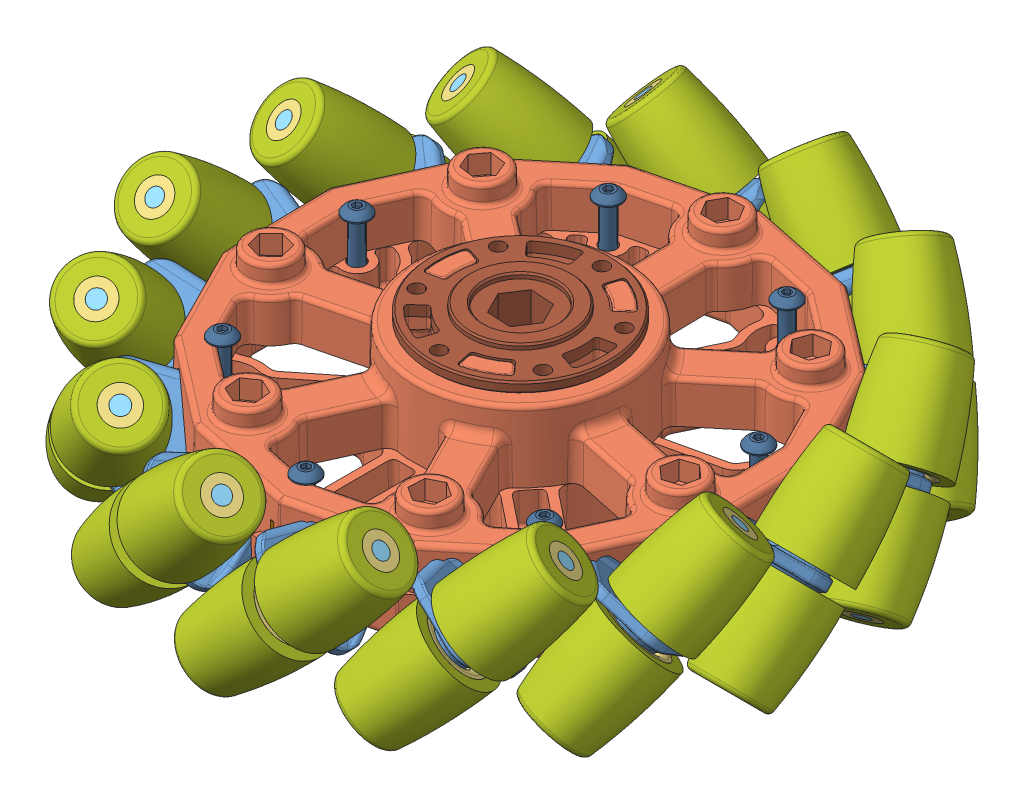
SolidWorks assembly 8in mecanum left vex 217-2801, configuration Default. Lengths in mm.
Overall size (213.38 67.99 218.38).
149 component instances, 11 part files, 3 mates.
Components (placement in the parent):
- 217-2799-002 Rev1-1: 217-2799-002 Rev1 [Default] at (67.5204 0 0) x (0 0 -1) z (1 0 0) size (26.84 25.28 30.09)
- 217-2801-001 Rev1-1: 217-2801-001 Rev1 [Default] at (-0.0396 6.3542 -0.0405) x (1 0 0) z (0 -1 0) size (148.4 151.99 28.55)
- 217-2801-001 Rev1-2: 217-2801-001 Rev1 [Default] at (0.6081 -6.3458 -2.0155) x (-0.892252 0 0.451538) z (0 1 0) size (148.4 151.99 28.55)
- 217-2586-003 Rev2-1: 217-2586-003 Rev2 [Default] at (88.2976 -4.0062 4.0062) x (-0.854327 -0.367509 -0.367509) z (-0.519737 0.6041 0.6041) size (19.46 28.57 19.46)
- 217-2586-003 Rev2-2: 217-2586-003 Rev2 [Default] at (88.2976 4.0062 -4.0062) x (0.717269 -0.492709 -0.492709) z (0.696796 0.507186 0.507186) size (19.46 28.57 19.46)
- 217-2586-005 Rev2-1: 217-2586-005 Rev2 [Default] at (88.2976 -6.3286 6.3286) x (0 0.707107 -0.707107) z (0.473193 -0.622932 -0.622932) size (8.5 8 8)
- 217-2586-005 Rev2-2: 217-2586-005 Rev2 [Default] at (88.2976 6.3286 -6.3286) x (0 0.707107 -0.707107) z (0.707107 -0.5 -0.5) size (8.5 8 8)
- 217-2586-007 Rev1-1: 217-2586-007 Rev1 [Default] at (88.2976 0 0) x (0 0.707107 -0.707107) z (0.543569 -0.59352 -0.59352) size (61.72 5 5)
- 217-2586-008 Rev1-1: 217-2586-008 Rev1 [Default] at (-11.9459 2.5442 -20.6627) x (0.866025 0 -0.5) z (0 -1 0) size (7.33 6.35 31.75)
- 217-2587-002 Rev2-1: 217-2587-002 Rev2 [Default] at (88.2976 -0.3986 0.3986) x (-0.963241 0.189956 0.189956) z (-0.268638 -0.681114 -0.681114) size (26.1 28.57 26.1)
- 217-2587-002 Rev2-2: 217-2587-002 Rev2 [Default] at (88.2976 0.3986 -0.3986) x (0.779223 -0.443177 -0.443177) z (-0.626747 -0.550994 -0.550994) size (26.1 28.57 26.1)
- NUT-832-NYLOCK-1: NUT-832-NYLOCK [Default] at (-49.6859 -13.6521 39.5511) x (-0.365341 0 0.930874) z (0.930874 0 0.365341) size (10.2 5.86 8.12)
- PINL-M050-0012-S-1: PINL-M050-0012-S [Default] at (-69.318 -0.0958 -15.8528) x (0 -1 0) z (-0.272222 0 0.962235) size (12 5 5)
- SCREW-832-1250-1: SCREW-832-1250 [Default] at (-49.6859 14.914 39.5511) x (0 -1 0) z (-0.321403 0 -0.946943) size (33.96 7.92 7.92)
- 217-2586-008 Rev1-2: 217-2586-008 Rev1 [Default] at (-23.8521 2.5442 -0.0405) x (0 0 -1) z (0 -1 0) size (7.33 6.35 31.75)
- 217-2586-008 Rev1-3: 217-2586-008 Rev1 [Default] at (-15.8036 2.5442 6.5601) x (-0.667084 0 -0.744983) z (0 -1 0) size (7.33 6.35 31.75)
- 217-2586-008 Rev1-4: 217-2586-008 Rev1 [Default] at (11.8666 2.5442 20.5817) x (-0.866025 0 0.5) z (0 -1 0) size (7.33 6.35 31.75)
- 217-2586-008 Rev1-5: 217-2586-008 Rev1 [Default] at (23.7729 2.5442 -0.0405) x (0 0 1) z (0 -1 0) size (7.33 6.35 31.75)
- 217-2586-008 Rev1-6: 217-2586-008 Rev1 [Default] at (11.8666 2.5442 -20.6627) x (0.866025 0 0.5) z (0 -1 0) size (7.33 6.35 31.75)
- NUT-832-NYLOCK-2: NUT-832-NYLOCK [Default] at (-0.0396 -13.6521 63.4595) x (0.5 0 0.866025) z (0.866025 0 -0.5) size (10.2 5.86 8.12)
- NUT-832-NYLOCK-3: NUT-832-NYLOCK [Default] at (49.6067 -13.6521 39.5511) x (0.988831 0 0.149042) z (0.149042 0 -0.988831) size (10.2 5.86 8.12)
- NUT-832-NYLOCK-4: NUT-832-NYLOCK [Default] at (61.8683 -13.6521 -14.1706) x (0.733052 0 -0.680173) z (-0.680173 0 -0.733052) size (10.2 5.86 8.12)
- NUT-832-NYLOCK-5: NUT-832-NYLOCK [Default] at (27.512 -13.6521 -57.252) x (-0.07473 0 -0.997204) z (-0.997204 0 0.07473) size (10.2 5.86 8.12)
- NUT-832-NYLOCK-6: NUT-832-NYLOCK [Default] at (-27.5912 -13.6521 -57.252) x (-0.826239 0 -0.56332) z (-0.56332 0 0.826239) size (10.2 5.86 8.12)
- NUT-832-NYLOCK-7: NUT-832-NYLOCK [Default] at (-61.9475 -13.6521 -14.1706) x (-0.955573 0 0.294755) z (0.294755 0 0.955573) size (10.2 5.86 8.12)
- SCREW-832-1250-2: SCREW-832-1250 [Default] at (-0.0396 14.914 63.4595) x (0 -1 0) z (-0.940741 0 -0.339126) size (33.96 7.92 7.92)
- SCREW-832-1250-3: SCREW-832-1250 [Default] at (49.6067 14.914 39.5511) x (0 -1 0) z (-0.851682 0 0.524059) size (33.96 7.92 7.92)
- SCREW-832-1250-4: SCREW-832-1250 [Default] at (61.8683 14.914 -14.1706) x (0 -1 0) z (-0.121289 0 0.992617) size (33.96 7.92 7.92)
- SCREW-832-1250-5: SCREW-832-1250 [Default] at (27.512 14.914 -57.252) x (0 -1 0) z (0.700437 0 0.713714) size (33.96 7.92 7.92)
- SCREW-832-1250-6: SCREW-832-1250 [Default] at (-27.5912 14.914 -57.252) x (0 -1 0) z (0.99472 0 -0.10263) size (33.96 7.92 7.92)
- SCREW-832-1250-7: SCREW-832-1250 [Default] at (-61.9475 14.914 -14.1706) x (0 -1 0) z (0.539958 0 -0.841692) size (33.96 7.92 7.92)
- PINL-M050-0012-S-2: PINL-M050-0012-S [Default] at (-69.318 -0.0958 15.7719) x (0 -1 0) z (0.172235 0 0.985056) size (12 5 5)
- PINL-M050-0012-S-3: PINL-M050-0012-S [Default] at (-55.5966 -0.0958 44.2647) x (0 -1 0) z (0.582578 0 0.812775) size (12 5 5)
- PINL-M050-0012-S-4: PINL-M050-0012-S [Default] at (-30.8714 -0.0958 63.9824) x (0 -1 0) z (0.877534 0 0.479514) size (12 5 5)
- PINL-M050-0012-S-5: PINL-M050-0012-S [Default] at (-0.0396 -0.0958 71.0195) x (0 -1 0) z (0.998684 0 0.051279) size (12 5 5)
- PINL-M050-0012-S-6: PINL-M050-0012-S [Default] at (30.7922 -0.0958 63.9824) x (0 -1 0) z (0.922033 0 -0.387112) size (12 5 5)
- PINL-M050-0012-S-7: PINL-M050-0012-S [Default] at (55.5173 -0.0958 44.2647) x (0 -1 0) z (0.662761 0 -0.748831) size (12 5 5)
- PINL-M050-0012-S-8: PINL-M050-0012-S [Default] at (69.2388 -0.0958 15.7719) x (0 -1 0) z (0.272222 0 -0.962235) size (12 5 5)
- PINL-M050-0012-S-9: PINL-M050-0012-S [Default] at (69.2388 -0.0958 -15.8528) x (0 -1 0) z (-0.172235 0 -0.985056) size (12 5 5)
- PINL-M050-0012-S-10: PINL-M050-0012-S [Default] at (55.5173 -0.0958 -44.3457) x (0 -1 0) z (-0.582578 0 -0.812775) size (12 5 5)
- PINL-M050-0012-S-11: PINL-M050-0012-S [Default] at (30.7922 -0.0958 -64.0633) x (0 -1 0) z (-0.877534 0 -0.479514) size (12 5 5)
- PINL-M050-0012-S-12: PINL-M050-0012-S [Default] at (-0.0396 -0.0958 -71.1005) x (0 -1 0) z (-0.998684 0 -0.051279) size (12 5 5)
- PINL-M050-0012-S-13: PINL-M050-0012-S [Default] at (-30.8714 -0.0958 -64.0633) x (0 -1 0) z (-0.922033 0 0.387112) size (12 5 5)
- PINL-M050-0012-S-14: PINL-M050-0012-S [Default] at (-55.5966 -0.0958 -44.3457) x (0 -1 0) z (-0.662761 0 0.748831) size (12 5 5)
- 217-2587-002 Rev2-3: 217-2587-002 Rev2 [Default] at (79.3941 0.3986 -38.6912) x (0.509769 -0.443177 -0.737381) z (-0.803746 -0.550994 -0.224493) size (26.1 28.57 26.1)
- 217-2587-002 Rev2-4: 217-2587-002 Rev2 [Default] at (54.7578 0.3986 -69.3286) x (0.139348 -0.443177 -0.885537) z (-0.821555 -0.550994 0.146471) size (26.1 28.57 26.1)
- 217-2587-002 Rev2-5: 217-2587-002 Rev2 [Default] at (19.2682 0.3986 -86.2426) x (-0.258672 -0.443177 -0.858303) z (-0.676644 -0.550994 0.488425) size (26.1 28.57 26.1)
- 217-2587-002 Rev2-6: 217-2587-002 Rev2 [Default] at (-20.0456 0.3986 -86.0832) x (-0.605459 -0.443177 -0.66107) z (-0.397715 -0.550994 0.73364) size (26.1 28.57 26.1)
- 217-2587-002 Rev2-7: 217-2587-002 Rev2 [Default] at (-55.3969 0.3986 -68.882) x (-0.832327 -0.443177 -0.332905) z (-0.040014 -0.550994 0.833549) size (26.1 28.57 26.1)
- 217-2587-002 Rev2-8: 217-2587-002 Rev2 [Default] at (-79.784 0.3986 -38.0459) x (-0.894343 -0.443177 0.061196) z (0.325612 -0.550994 0.768364) size (26.1 28.57 26.1)
- 217-2587-002 Rev2-9: 217-2587-002 Rev2 [Default] at (-88.3768 0.3986 0.3176) x (-0.779223 -0.443177 0.443177) z (0.626747 -0.550994 0.550994) size (26.1 28.57 26.1)
- 217-2587-002 Rev2-10: 217-2587-002 Rev2 [Default] at (-79.4733 0.3986 38.6102) x (-0.509769 -0.443177 0.737381) z (0.803746 -0.550994 0.224493) size (26.1 28.57 26.1)
- 217-2587-002 Rev2-11: 217-2587-002 Rev2 [Default] at (-54.837 0.3986 69.2476) x (-0.139348 -0.443177 0.885537) z (0.821555 -0.550994 -0.146471) size (26.1 28.57 26.1)
- 217-2587-002 Rev2-12: 217-2587-002 Rev2 [Default] at (-19.3474 0.3986 86.1616) x (0.258672 -0.443177 0.858303) z (0.676644 -0.550994 -0.488425) size (26.1 28.57 26.1)
- 217-2587-002 Rev2-13: 217-2587-002 Rev2 [Default] at (19.9664 0.3986 86.0022) x (0.605459 -0.443177 0.66107) z (0.397715 -0.550994 -0.73364) size (26.1 28.57 26.1)
- 217-2587-002 Rev2-14: 217-2587-002 Rev2 [Default] at (55.3177 0.3986 68.8011) x (0.832327 -0.443177 0.332905) z (0.040014 -0.550994 -0.833549) size (26.1 28.57 26.1)
- 217-2587-002 Rev2-15: 217-2587-002 Rev2 [Default] at (79.7048 0.3986 37.965) x (0.894343 -0.443177 -0.061196) z (-0.325612 -0.550994 -0.768364) size (26.1 28.57 26.1)
- 217-2587-002 Rev2-16: 217-2587-002 Rev2 [Default] at (79.74 -0.3986 -37.973) x (-0.785432 0.189956 0.589079) z (-0.537559 -0.681114 -0.497105) size (26.1 28.57 26.1)
- 217-2587-002 Rev2-17: 217-2587-002 Rev2 [Default] at (55.381 -0.3986 -68.8315) x (-0.452058 0.189956 0.871528) z (-0.70001 -0.681114 -0.214638) size (26.1 28.57 26.1)
- 217-2587-002 Rev2-18: 217-2587-002 Rev2 [Default] at (20.0453 -0.3986 -86.0652) x (-0.029148 0.189956 0.98136) z (-0.723815 -0.681114 0.110341) size (26.1 28.57 26.1)
- 217-2587-002 Rev2-19: 217-2587-002 Rev2 [Default] at (-19.2684 -0.3986 -86.2606) x (0.399535 0.189956 0.896822) z (-0.60426 -0.681114 0.413465) size (26.1 28.57 26.1)
- 217-2587-002 Rev2-20: 217-2587-002 Rev2 [Default] at (-54.7737 -0.3986 -69.379) x (0.749084 0.189956 0.634657) z (-0.365024 -0.681114 0.634698) size (26.1 28.57 26.1)
- 217-2587-002 Rev2-21: 217-2587-002 Rev2 [Default] at (-79.4382 -0.3986 -38.7641) x (0.950269 0.189956 0.24679) z (-0.05349 -0.681114 0.730221) size (26.1 28.57 26.1)
- 217-2587-002 Rev2-22: 217-2587-002 Rev2 [Default] at (-88.3768 -0.3986 -0.4795) x (0.963241 0.189956 -0.189956) z (0.268638 -0.681114 0.681114) size (26.1 28.57 26.1)
- 217-2587-002 Rev2-23: 217-2587-002 Rev2 [Default] at (-79.8192 -0.3986 37.892) x (0.785432 0.189956 -0.589079) z (0.537559 -0.681114 0.497105) size (26.1 28.57 26.1)
- 217-2587-002 Rev2-24: 217-2587-002 Rev2 [Default] at (-55.4602 -0.3986 68.7506) x (0.452058 0.189956 -0.871528) z (0.70001 -0.681114 0.214638) size (26.1 28.57 26.1)
- 217-2587-002 Rev2-25: 217-2587-002 Rev2 [Default] at (-20.1245 -0.3986 85.9842) x (0.029148 0.189956 -0.98136) z (0.723815 -0.681114 -0.110341) size (26.1 28.57 26.1)
- 217-2587-002 Rev2-26: 217-2587-002 Rev2 [Default] at (19.1892 -0.3986 86.1796) x (-0.399535 0.189956 -0.896822) z (0.60426 -0.681114 -0.413465) size (26.1 28.57 26.1)
- 217-2587-002 Rev2-27: 217-2587-002 Rev2 [Default] at (54.6945 -0.3986 69.2981) x (-0.749084 0.189956 -0.634657) z (0.365024 -0.681114 -0.634698) size (26.1 28.57 26.1)
- 217-2587-002 Rev2-28: 217-2587-002 Rev2 [Default] at (79.359 -0.3986 38.6832) x (-0.950269 0.189956 -0.24679) z (0.05349 -0.681114 -0.730221) size (26.1 28.57 26.1)
- 217-2586-007 Rev1-2: 217-2586-007 Rev1 [Default] at (79.567 0 -38.3321) x (-0.306802 0.707107 -0.637081) z (0.23222 -0.59352 -0.770589) size (61.72 5 5)
- 217-2586-007 Rev1-3: 217-2586-007 Rev1 [Default] at (55.0694 0 -69.08) x (-0.552838 0.707107 -0.440874) z (-0.125123 -0.59352 -0.795033) size (61.72 5 5)
- 217-2586-007 Rev1-4: 217-2586-007 Rev1 [Default] at (19.6567 0 -86.1539) x (-0.689378 0.707107 -0.157346) z (-0.457684 -0.59352 -0.662011) size (61.72 5 5)
- 217-2586-007 Rev1-5: 217-2586-007 Rev1 [Default] at (-19.657 0 -86.1719) x (-0.689378 0.707107 0.157346) z (-0.699595 -0.59352 -0.39787) size (61.72 5 5)
- 217-2586-007 Rev1-6: 217-2586-007 Rev1 [Default] at (-55.0853 0 -69.1305) x (-0.552838 0.707107 0.440874) z (-0.802943 -0.59352 -0.054926) size (61.72 5 5)
- 217-2586-007 Rev1-7: 217-2586-007 Rev1 [Default] at (-79.6111 0 -38.405) x (-0.306802 0.707107 0.637081) z (-0.747258 -0.59352 0.298897) size (61.72 5 5)
- 217-2586-007 Rev1-8: 217-2586-007 Rev1 [Default] at (-88.3768 0 -0.081) x (0 0.707107 0.707107) z (-0.543569 -0.59352 0.59352) size (61.72 5 5)
- 217-2586-007 Rev1-9: 217-2586-007 Rev1 [Default] at (-79.6462 0 38.2511) x (0.306802 0.707107 0.637081) z (-0.23222 -0.59352 0.770589) size (61.72 5 5)
- 217-2586-007 Rev1-10: 217-2586-007 Rev1 [Default] at (-55.1486 0 68.9991) x (0.552838 0.707107 0.440874) z (0.125123 -0.59352 0.795033) size (61.72 5 5)
- 217-2586-007 Rev1-11: 217-2586-007 Rev1 [Default] at (-19.736 0 86.0729) x (0.689378 0.707107 0.157346) z (0.457684 -0.59352 0.662011) size (61.72 5 5)
- 217-2586-007 Rev1-12: 217-2586-007 Rev1 [Default] at (19.5778 0 86.0909) x (0.689378 0.707107 -0.157346) z (0.699595 -0.59352 0.39787) size (61.72 5 5)
- 217-2586-007 Rev1-13: 217-2586-007 Rev1 [Default] at (55.0061 0 69.0496) x (0.552838 0.707107 -0.440874) z (0.802943 -0.59352 0.054926) size (61.72 5 5)
- 217-2586-007 Rev1-14: 217-2586-007 Rev1 [Default] at (79.5319 0 38.3241) x (0.306802 0.707107 -0.637081) z (0.747258 -0.59352 -0.298897) size (61.72 5 5)
- 217-2586-005 Rev2-3: 217-2586-005 Rev2 [Default] at (76.8211 6.3286 -44.034) x (-0.306802 0.707107 -0.637081) z (0.420139 -0.5 -0.757287) size (8.5 8 8)
- 217-2586-005 Rev2-4: 217-2586-005 Rev2 [Default] at (50.1215 6.3286 -73.0259) x (-0.552838 0.707107 -0.440874) z (0.049958 -0.5 -0.864583) size (8.5 8 8)
- 217-2586-005 Rev2-5: 217-2586-005 Rev2 [Default] at (13.4868 6.3286 -87.5621) x (-0.689378 0.707107 -0.157346) z (-0.330118 -0.5 -0.800639) size (8.5 8 8)
- 217-2586-005 Rev2-6: 217-2586-005 Rev2 [Default] at (-25.827 6.3286 -84.7636) x (-0.689378 0.707107 0.157346) z (-0.64481 -0.5 -0.578118) size (8.5 8 8)
- 217-2586-005 Rev2-7: 217-2586-005 Rev2 [Default] at (-60.0332 6.3286 -65.1847) x (-0.552838 0.707107 0.440874) z (-0.83179 -0.5 -0.241093) size (8.5 8 8)
- 217-2586-005 Rev2-8: 217-2586-005 Rev2 [Default] at (-82.357 6.3286 -32.7032) x (-0.306802 0.707107 0.637081) z (-0.854023 -0.5 0.143682) size (8.5 8 8)
- 217-2586-005 Rev2-9: 217-2586-005 Rev2 [Default] at (-88.3768 6.3286 6.2476) x (0 0.707107 0.707107) z (-0.707107 -0.5 0.5) size (8.5 8 8)
- 217-2586-005 Rev2-10: 217-2586-005 Rev2 [Default] at (-76.9004 6.3286 43.953) x (0.306802 0.707107 0.637081) z (-0.420139 -0.5 0.757287) size (8.5 8 8)
- 217-2586-005 Rev2-11: 217-2586-005 Rev2 [Default] at (-50.2007 6.3286 72.9449) x (0.552838 0.707107 0.440874) z (-0.049958 -0.5 0.864583) size (8.5 8 8)
- 217-2586-005 Rev2-12: 217-2586-005 Rev2 [Default] at (-13.566 6.3286 87.4812) x (0.689378 0.707107 0.157346) z (0.330118 -0.5 0.800639) size (8.5 8 8)
- 217-2586-005 Rev2-13: 217-2586-005 Rev2 [Default] at (25.7477 6.3286 84.6827) x (0.689378 0.707107 -0.157346) z (0.64481 -0.5 0.578118) size (8.5 8 8)
- 217-2586-005 Rev2-14: 217-2586-005 Rev2 [Default] at (59.954 6.3286 65.1037) x (0.552838 0.707107 -0.440874) z (0.83179 -0.5 0.241093) size (8.5 8 8)
- 217-2586-005 Rev2-15: 217-2586-005 Rev2 [Default] at (82.2778 6.3286 32.6222) x (0.306802 0.707107 -0.637081) z (0.854023 -0.5 -0.143682) size (8.5 8 8)
- 217-2586-005 Rev2-16: 217-2586-005 Rev2 [Default] at (82.3129 -6.3286 -32.6302) x (-0.306802 0.707107 -0.637081) z (0.156052 -0.622932 -0.766553) size (8.5 8 8)
- 217-2586-005 Rev2-17: 217-2586-005 Rev2 [Default] at (60.0173 -6.3286 -65.1342) x (-0.552838 0.707107 -0.440874) z (-0.191997 -0.622932 -0.758349) size (8.5 8 8)
- 217-2586-005 Rev2-18: 217-2586-005 Rev2 [Default] at (25.8267 -6.3286 -84.7456) x (-0.689378 0.707107 -0.157346) z (-0.502019 -0.622932 -0.599944) size (8.5 8 8)
- 217-2586-005 Rev2-19: 217-2586-005 Rev2 [Default] at (-13.4871 -6.3286 -87.5801) x (-0.689378 0.707107 0.157346) z (-0.712609 -0.622932 -0.322713) size (8.5 8 8)
- 217-2586-005 Rev2-20: 217-2586-005 Rev2 [Default] at (-50.1374 -6.3286 -73.0764) x (-0.552838 0.707107 0.440874) z (-0.782059 -0.622932 0.018435) size (8.5 8 8)
- 217-2586-005 Rev2-21: 217-2586-005 Rev2 [Default] at (-76.8652 -6.3286 -44.1069) x (-0.306802 0.707107 0.637081) z (-0.696612 -0.622932 0.355932) size (8.5 8 8)
- 217-2586-005 Rev2-22: 217-2586-005 Rev2 [Default] at (-88.3768 -6.3286 -6.4096) x (0 0.707107 0.707107) z (-0.473193 -0.622932 0.622932) size (8.5 8 8)
- 217-2586-005 Rev2-23: 217-2586-005 Rev2 [Default] at (-82.3921 -6.3286 32.5492) x (0.306802 0.707107 0.637081) z (-0.156052 -0.622932 0.766553) size (8.5 8 8)
- 217-2586-005 Rev2-24: 217-2586-005 Rev2 [Default] at (-60.0965 -6.3286 65.0533) x (0.552838 0.707107 0.440874) z (0.191997 -0.622932 0.758349) size (8.5 8 8)
- 217-2586-005 Rev2-25: 217-2586-005 Rev2 [Default] at (-25.9059 -6.3286 84.6647) x (0.689378 0.707107 0.157346) z (0.502019 -0.622932 0.599944) size (8.5 8 8)
- 217-2586-005 Rev2-26: 217-2586-005 Rev2 [Default] at (13.4079 -6.3286 87.4992) x (0.689378 0.707107 -0.157346) z (0.712609 -0.622932 0.322713) size (8.5 8 8)
- 217-2586-005 Rev2-27: 217-2586-005 Rev2 [Default] at (50.0582 -6.3286 72.9954) x (0.552838 0.707107 -0.440874) z (0.782059 -0.622932 -0.018435) size (8.5 8 8)
- 217-2586-005 Rev2-28: 217-2586-005 Rev2 [Default] at (76.786 -6.3286 44.0259) x (0.306802 0.707107 -0.637081) z (0.696612 -0.622932 -0.355932) size (8.5 8 8)
- 217-2586-003 Rev2-3: 217-2586-003 Rev2 [Default] at (77.8288 4.0062 -41.9416) x (0.432459 -0.492709 -0.755127) z (0.847851 0.507186 0.15463) size (19.46 28.57 19.46)
- 217-2586-003 Rev2-4: 217-2586-003 Rev2 [Default] at (51.9372 4.0062 -71.5779) x (0.061995 -0.492709 -0.867983) z (0.830979 0.507186 -0.228552) size (19.46 28.57 19.46)
- 217-2586-003 Rev2-5: 217-2586-003 Rev2 [Default] at (15.7509 4.0062 -87.0453) x (-0.320749 -0.492709 -0.808924) z (0.649521 0.507186 -0.566466) size (19.46 28.57 19.46)
- 217-2586-003 Rev2-6: 217-2586-003 Rev2 [Default] at (-23.5628 4.0062 -85.2804) x (-0.639963 -0.492709 -0.589648) z (0.339418 0.507186 -0.792185) size (19.46 28.57 19.46)
- 217-2586-003 Rev2-7: 217-2586-003 Rev2 [Default] at (-58.2175 4.0062 -66.6327) x (-0.832426 -0.492709 -0.253585) z (-0.037911 0.507186 -0.861002) size (19.46 28.57 19.46)
- 217-2586-003 Rev2-8: 217-2586-003 Rev2 [Default] at (-81.3494 4.0062 -34.7955) x (-0.860016 -0.492709 0.132704) z (-0.407732 0.507186 -0.759287) size (19.46 28.57 19.46)
- 217-2586-003 Rev2-9: 217-2586-003 Rev2 [Default] at (-88.3768 4.0062 3.9253) x (-0.717269 -0.492709 0.492709) z (-0.696796 0.507186 -0.507186) size (19.46 28.57 19.46)
- 217-2586-003 Rev2-10: 217-2586-003 Rev2 [Default] at (-77.908 4.0062 41.8606) x (-0.432459 -0.492709 0.755127) z (-0.847851 0.507186 -0.15463) size (19.46 28.57 19.46)
- 217-2586-003 Rev2-11: 217-2586-003 Rev2 [Default] at (-52.0164 4.0062 71.4969) x (-0.061995 -0.492709 0.867983) z (-0.830979 0.507186 0.228552) size (19.46 28.57 19.46)
- 217-2586-003 Rev2-12: 217-2586-003 Rev2 [Default] at (-15.8302 4.0062 86.9644) x (0.320749 -0.492709 0.808924) z (-0.649521 0.507186 0.566466) size (19.46 28.57 19.46)
- 217-2586-003 Rev2-13: 217-2586-003 Rev2 [Default] at (23.4836 4.0062 85.1995) x (0.639963 -0.492709 0.589648) z (-0.339418 0.507186 0.792185) size (19.46 28.57 19.46)
- 217-2586-003 Rev2-14: 217-2586-003 Rev2 [Default] at (58.1383 4.0062 66.5517) x (0.832426 -0.492709 0.253585) z (0.037911 0.507186 0.861002) size (19.46 28.57 19.46)
- 217-2586-003 Rev2-15: 217-2586-003 Rev2 [Default] at (81.2701 4.0062 34.7146) x (0.860016 -0.492709 -0.132704) z (0.407732 0.507186 0.759287) size (19.46 28.57 19.46)
- 217-2586-003 Rev2-16: 217-2586-003 Rev2 [Default] at (81.3053 -4.0062 -34.7226) x (-0.929178 -0.367509 0.039564) z (-0.206157 0.6041 0.769781) size (19.46 28.57 19.46)
- 217-2586-003 Rev2-17: 217-2586-003 Rev2 [Default] at (58.2016 -4.0062 -66.5822) x (-0.819994 -0.367509 0.438801) z (0.148254 0.6041 0.782997) size (19.46 28.57 19.46)
- 217-2586-003 Rev2-18: 217-2586-003 Rev2 [Default] at (23.5625 -4.0062 -85.2624) x (-0.548401 -0.367509 0.751128) z (0.473302 0.6041 0.641131) size (19.46 28.57 19.46)
- 217-2586-003 Rev2-19: 217-2586-003 Rev2 [Default] at (-15.7512 -4.0062 -87.0634) x (-0.16819 -0.367509 0.914685) z (0.704606 0.6041 0.372281) size (19.46 28.57 19.46)
- 217-2586-003 Rev2-20: 217-2586-003 Rev2 [Default] at (-51.9531 -4.0062 -71.6284) x (0.245334 -0.367509 0.897078) z (0.796355 0.6041 0.029696) size (19.46 28.57 19.46)
- 217-2586-003 Rev2-21: 217-2586-003 Rev2 [Default] at (-77.8729 -4.0062 -42.0145) x (0.610265 -0.367509 0.701793) z (0.730376 0.6041 -0.31877) size (19.46 28.57 19.46)
- 217-2586-003 Rev2-22: 217-2586-003 Rev2 [Default] at (-88.3768 -4.0062 -4.0872) x (0.854327 -0.367509 0.367509) z (0.519737 0.6041 -0.6041) size (19.46 28.57 19.46)
- 217-2586-003 Rev2-23: 217-2586-003 Rev2 [Default] at (-81.3845 -4.0062 34.6416) x (0.929178 -0.367509 -0.039564) z (0.206157 0.6041 -0.769781) size (19.46 28.57 19.46)
- 217-2586-003 Rev2-24: 217-2586-003 Rev2 [Default] at (-58.2808 -4.0062 66.5012) x (0.819994 -0.367509 -0.438801) z (-0.148254 0.6041 -0.782997) size (19.46 28.57 19.46)
- 217-2586-003 Rev2-25: 217-2586-003 Rev2 [Default] at (-23.6417 -4.0062 85.1814) x (0.548401 -0.367509 -0.751128) z (-0.473302 0.6041 -0.641131) size (19.46 28.57 19.46)
- 217-2586-003 Rev2-26: 217-2586-003 Rev2 [Default] at (15.672 -4.0062 86.9824) x (0.16819 -0.367509 -0.914685) z (-0.704606 0.6041 -0.372281) size (19.46 28.57 19.46)
- 217-2586-003 Rev2-27: 217-2586-003 Rev2 [Default] at (51.8739 -4.0062 71.5474) x (-0.245334 -0.367509 -0.897078) z (-0.796355 0.6041 -0.029696) size (19.46 28.57 19.46)
- 217-2586-003 Rev2-28: 217-2586-003 Rev2 [Default] at (77.7937 -4.0062 41.9336) x (-0.610265 -0.367509 -0.701793) z (-0.730376 0.6041 0.31877) size (19.46 28.57 19.46)
- 217-2799-002 Rev1-2: 217-2799-002 Rev1 [Default] at (60.8474 0 -29.3172) x (-0.433884 0 -0.900969) z (0.900969 0 -0.433884) size (26.84 25.28 30.09)
- 217-2799-002 Rev1-3: 217-2799-002 Rev1 [Default] at (42.115 0 -52.8358) x (-0.781831 0 -0.62349) z (0.62349 0 -0.781831) size (26.84 25.28 30.09)
- 217-2799-002 Rev1-4: 217-2799-002 Rev1 [Default] at (15.0334 0 -65.8976) x (-0.974928 0 -0.222521) z (0.222521 0 -0.974928) size (26.84 25.28 30.09)
- 217-2799-002 Rev1-5: 217-2799-002 Rev1 [Default] at (-15.0337 0 -65.9156) x (-0.974928 0 0.222521) z (-0.222521 0 -0.974928) size (26.84 25.28 30.09)
- 217-2799-002 Rev1-6: 217-2799-002 Rev1 [Default] at (-42.1309 0 -52.8863) x (-0.781831 0 0.62349) z (-0.62349 0 -0.781831) size (26.84 25.28 30.09)
- 217-2799-002 Rev1-7: 217-2799-002 Rev1 [Default] at (-60.8915 0 -29.3901) x (-0.433884 0 0.900969) z (-0.900969 0 -0.433884) size (26.84 25.28 30.09)
- 217-2799-002 Rev1-8: 217-2799-002 Rev1 [Default] at (-67.5996 0 -0.081) x (0 0 1) z (-1 0 0) size (26.84 25.28 30.09)
- 217-2799-002 Rev1-9: 217-2799-002 Rev1 [Default] at (-60.9266 0 29.2362) x (0.433884 0 0.900969) z (-0.900969 0 0.433884) size (26.84 25.28 30.09)
- 217-2799-002 Rev1-10: 217-2799-002 Rev1 [Default] at (-42.1942 0 52.7548) x (0.781831 0 0.62349) z (-0.62349 0 0.781831) size (26.84 25.28 30.09)
- 217-2799-002 Rev1-11: 217-2799-002 Rev1 [Default] at (-15.1126 0 65.8166) x (0.974928 0 0.222521) z (-0.222521 0 0.974928) size (26.84 25.28 30.09)
- 217-2799-002 Rev1-12: 217-2799-002 Rev1 [Default] at (14.9544 0 65.8347) x (0.974928 0 -0.222521) z (0.222521 0 0.974928) size (26.84 25.28 30.09)
- 217-2799-002 Rev1-13: 217-2799-002 Rev1 [Default] at (42.0517 0 52.8053) x (0.781831 0 -0.62349) z (0.62349 0 0.781831) size (26.84 25.28 30.09)
- 217-2799-002 Rev1-14: 217-2799-002 Rev1 [Default] at (60.8123 0 29.3092) x (0.433884 0 -0.900969) z (0.900969 0 0.433884) size (26.84 25.28 30.09)
- Versahub 0.5in hex-1: Versahub 0.5in hex [Default] at (0.6081 12.0692 -2.0155) x (0 1 0) z (0.451538 0 0.892252) size (14.3 55.88 55.88)
Mates (geometry in assembly coordinates):
- Coincident1: coincident anti-aligned: plane of 217-2801-001 Rev1-2 through (0.6081 21.5942 -2.0155) normal (0 1 0); plane of Versahub 0.5in hex-1 through (-12.1466 21.5942 4.4392) normal (0 -1 0)
- Concentric1: concentric aligned: cylinder of 217-2801-001 Rev1-2 through (0.6081 21.5942 -2.0155) axis (0 -1 0) radius 14.3; cylinder of Versahub 0.5in hex-1 through (0.6081 12.0692 -2.0155) axis (0 -1 0) radius 14.295
- Coincident2: coincident aligned: plane of 217-2801-001 Rev1-2 through (-13.9529 18.4192 10.9548) normal (0.667084 0 0.744983); plane of Versahub 0.5in hex-1 through (-18.4223 21.5942 14.9579) normal (0.667084 0 0.744983)
